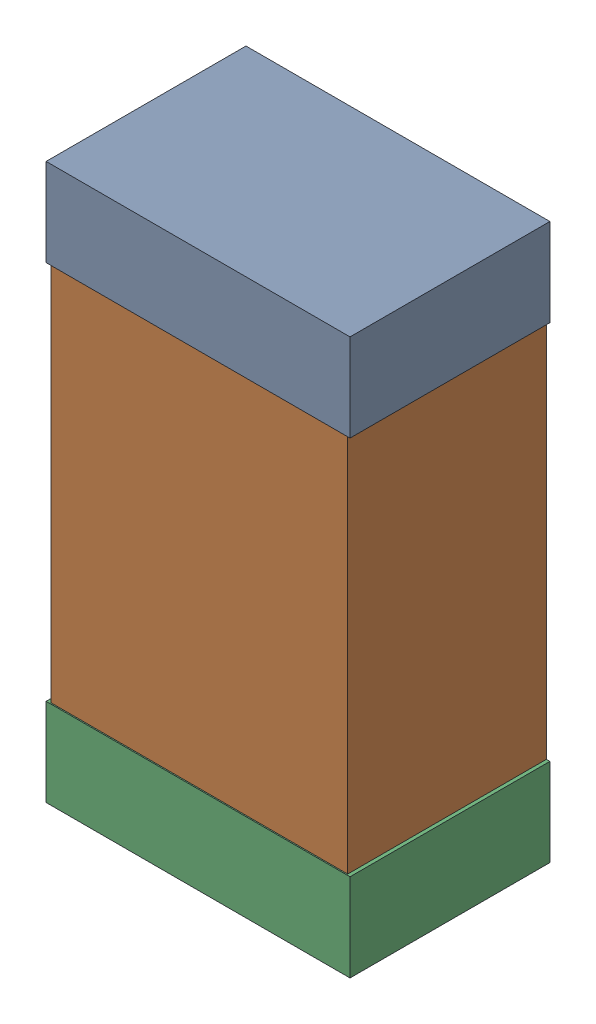
SolidWorks assembly C6Kanaloa_v2.0.0_Motor, configuration Default. Lengths in mm.
Overall size (1.3 2.38 0.85).
6 component instances, 2 part files, 0 mates.
Components (placement in the parent):
- 330415056-1: 330415056 [Default] at (112.268 105.453 0) size (1.3 0.38 0.85)
  - Extruded_2-1: Extruded_2 [Default] at origin size (1.3 0.38 0.85)
- 352877008-1: 352877008 [Default] at (112.268 104.453 0) size (1.27 2.2 0.85)
  - Extruded_3-1: Extruded_3 [Default] at origin size (1.27 2.2 0.85)
- 330415056-2: 330415056 [Default] at (112.268 103.453 0) size (1.3 0.38 0.85)
  - Extruded_2-1: Extruded_2 [Default] at origin size (1.3 0.38 0.85)
